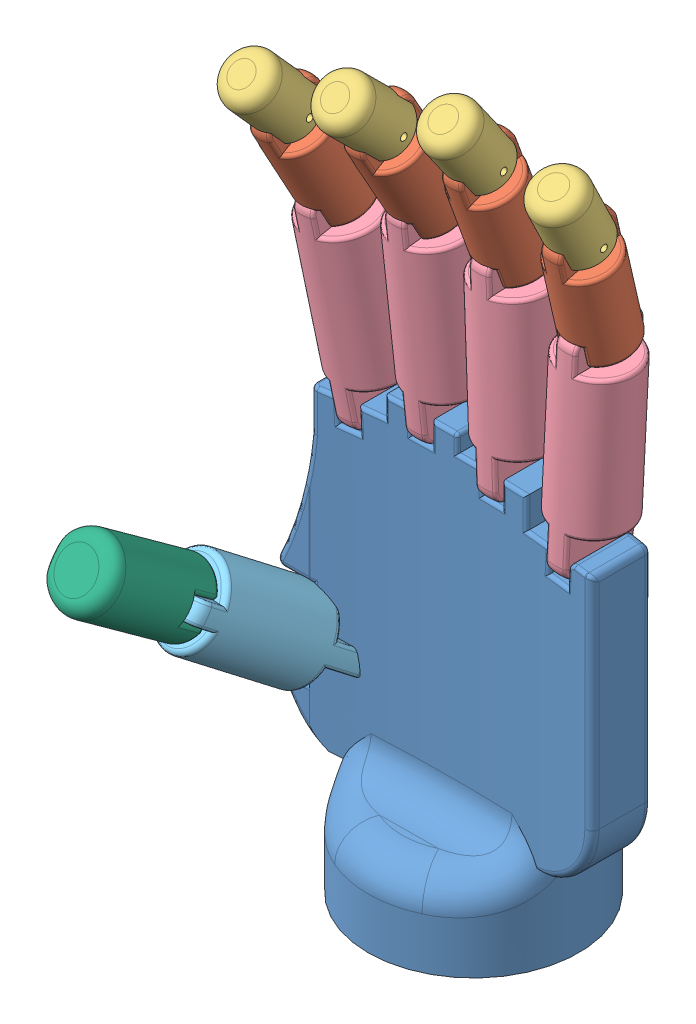
SolidWorks assembly Ensamblaje mano R, configuration Predeterminado. Lengths in mm.
Overall size (111.22 222.01 106.07).
15 component instances, 6 part files, 38 mates.
Components (placement in the parent):
- base de mano-1: base de mano [Predeterminado] at (3.3487 -3.4882 90) size (98.34 123.24 62)
- dedo 1.2-1: dedo 1.2 [Predeterminado] at (-6.9513 129.9804 122.3576) x (-1 0 0) z (0 -0.872955 -0.487801) size (18 18.07 36.32)
- dedo 1.1-1: dedo 1.1 [Predeterminado] at (-6.9513 140.0458 133.6656) x (-1 0 0) z (0 -0.704682 -0.709524) size (15 15 21)
- ded0 1.2-2: ded0 1.2 [Predeterminado] at (13.8487 99.4741 102.1423) x (1 0 0) z (0 -0.999383 -0.035119) size (21 21.03 64.5)
- dedo 1.2-2: dedo 1.2 [Predeterminado] at (13.8487 127.4833 113.3304) x (-1 0 0) z (0 -0.939617 -0.342227) size (18 18.07 36.32)
- dedo 1.1-2: dedo 1.1 [Predeterminado] at (13.8487 139.407 122.6313) x (1 0 0) z (0 -0.819026 -0.573756) size (15 15 21)
- ded0 1.2-3: ded0 1.2 [Predeterminado] at (37.5842 89.8924 100.0838) x (0.99863 -0.052336 0) z (-0.052336 -0.998629 -0.001373) size (21 21.03 64.5)
- dedo 1.2-3: dedo 1.2 [Predeterminado] at (39.0948 118.7167 108.6644) x (0.99863 -0.052336 0) z (-0.050534 -0.964246 -0.260145) size (18 18.07 36.32)
- dedo 1.1-3: dedo 1.1 [Predeterminado] at (39.782 131.8288 116.0778) x (0.99863 -0.052336 0) z (-0.046599 -0.889162 -0.455213) size (15 15 21)
- ded0 1.2-4: ded0 1.2 [Predeterminado] at (-30.7423 97.0382 110.1488) x (0.99863 0.052336 0) z (0.051607 -0.984711 -0.166374) size (21 21.03 64.5)
- dedo 1.2-4: dedo 1.2 [Predeterminado] at (-32.1183 123.2948 124.9268) x (-0.99863 -0.052336 0) z (0.04639 -0.885174 -0.462941) size (18 18.07 36.32)
- dedo 1.1-4: dedo 1.1 [Predeterminado] at (-32.6839 134.086 135.4832) x (0.99863 0.052336 0) z (0.039151 -0.747038 -0.663627) size (15 15 21)
- dedo 2.2-1: dedo 2.2 [Predeterminado] at (-34.4255 -31.0842 101.0623) x (0 0.819152 -0.573576) z (-0.241922 0.556539 0.79482) size (24 24.37 54.63)
- dedo 2.1-1: dedo 2.1 [Predeterminado] at (-48.9957 15.6091 167.7471) x (0 -0.819152 0.573576) z (0.069756 -0.572179 -0.817157) size (20 24.03 35.12)
- ded0 1.2-5: ded0 1.2 [Predeterminado] at (-6.9513 104.1554 106.5839) x (1 0 0) z (0 -0.994158 -0.107933) size (21 21.03 64.5)
Mates (geometry in assembly coordinates):
- Concéntrica3: concentric: cylinder of dedo 1.2-1 through (-3.9513 69.0706 182.5476) axis (-1 0 0) radius 1; cylinder of dedo 1.1-1 through (3.5487 69.0706 182.5476) axis (-1 0 0) radius 1
- Coincidente3: coincident: plane of dedo 1.2-1 through (-9.9513 59.8667 176.8653) normal (-1 0 0); plane of dedo 1.1-1 through (-9.9513 59.6122 183.2812) normal (1 0 0)
- Concéntrica4: concentric: cylinder of base de mano-1 through (23.3487 38.5118 100) axis (-1 0 0) radius 1; cylinder of ded0 1.2-2 through (7.8487 38.5118 100) axis (1 0 0) radius 1
- Coincidente4: coincident: plane of base de mano-1 through (10.8487 34.5118 110) normal (1 0 0); plane of ded0 1.2-2 through (10.8487 52.9112 101.9763) normal (-1 0 0)
- Concéntrica5: concentric: cylinder of ded0 1.2-2 through (10.8487 70.1008 148.6429) axis (1 0 0) radius 1; cylinder of dedo 1.2-2 through (19.8487 70.1008 148.6429) axis (-1 0 0) radius 1
- Coincidente5: coincident: plane of ded0 1.2-2 through (16.8487 76.0584 137.6198) normal (1 0 0); plane of dedo 1.2-2 through (16.8487 62.1839 153.87) normal (-1 0 0)
- Concéntrica6: concentric: cylinder of dedo 1.2-2 through (16.8487 77.8654 177.6207) axis (-1 0 0) radius 1; cylinder of dedo 1.1-2 through (3.3487 77.8654 177.6207) axis (1 0 0) radius 1
- Coincidente6: coincident: plane of dedo 1.2-2 through (16.8487 67.6191 174.1545) normal (1 0 0); plane of dedo 1.1-2 through (16.8487 86.8654 180.6207) normal (-1 0 0)
- Concéntrica7: concentric: cylinder of base de mano-1 through (24.9047 29.4733 100) axis (0.99863 -0.052336 0) radius 1; cylinder of ded0 1.2-3 through (28.3999 29.2901 100) axis (0.99863 -0.052336 0) radius 1
- Coincidente7: coincident: plane of base de mano-1 through (31.1865 25.1386 110) normal (0.99863 -0.052336 0); plane of ded0 1.2-3 through (32.1346 43.2301 103.4608) normal (-0.99863 0.052336 0)
- Concéntrica8: concentric: cylinder of ded0 1.2-3 through (32.7758 55.4645 151.66) axis (0.99863 -0.052336 0) radius 1; cylinder of dedo 1.2-3 through (29.7799 55.6215 151.66) axis (0.99863 -0.052336 0) radius 1
- Coincidente8: coincident: plane of ded0 1.2-3 through (39.1376 62.2107 141.3151) normal (0.99863 -0.052336 0); plane of dedo 1.2-3 through (39.261 64.5654 152.7166) normal (-0.99863 0.052336 0)
- Concéntrica9: concentric: cylinder of dedo 1.2-3 through (33.1033 61.7138 181) axis (0.99863 -0.052336 0) radius 1; cylinder of dedo 1.1-3 through (25.6136 62.1063 181) axis (0.99863 -0.052336 0) radius 1
- Coincidente9: coincident: plane of dedo 1.2-3 through (39.4902 68.9399 173.2546) normal (0.99863 -0.052336 0); plane of dedo 1.1-3 through (39.5662 70.3896 183.9937) normal (-0.99863 0.052336 0)
- Concéntrica10: concentric: cylinder of base de mano-1 through (-18.1073 37.468 100) axis (-0.99863 -0.052336 0) radius 1; cylinder of ded0 1.2-4 through (-33.5861 36.6568 100) axis (0.99863 0.052336 0) radius 1
- Coincidente10: coincident: plane of base de mano-1 through (-24.389 33.1333 110) normal (-0.99863 -0.052336 0); plane of ded0 1.2-4 through (-25.3047 50.6055 105.3948) normal (0.99863 0.052336 0)
- Concéntrica11: concentric: cylinder of ded0 1.2-4 through (-31.5798 55.6968 154.8311) axis (0.99863 0.052336 0) radius 1; cylinder of dedo 1.2-4 through (-22.5921 56.1678 154.8311) axis (-0.99863 -0.052336 0) radius 1
- Coincidente11: coincident: plane of ded0 1.2-4 through (-26.0299 64.4421 145.5728) normal (0.99863 0.052336 0); plane of dedo 1.2-4 through (-25.1199 47.0783 157.992) normal (-0.99863 -0.052336 0)
- Concéntrica12: concentric: cylinder of dedo 1.2-4 through (-25.6161 56.5478 184.8263) axis (-0.99863 -0.052336 0) radius 1; cylinder of dedo 1.1-4 through (-39.0976 55.8413 184.8263) axis (0.99863 0.052336 0) radius 1
- Coincidente12: coincident: plane of dedo 1.2-4 through (-31.1313 47.1402 178.9886) normal (-0.99863 -0.052336 0); plane of dedo 1.1-4 through (-32.0317 64.3195 189.7702) normal (0.99863 0.052336 0)
- Concéntrica13: concentric: cylinder of base de mano-1 through (-35.1513 -22.8613 98.8582) axis (0 -0.819152 0.573576) radius 1; cylinder of dedo 2.2-1 through (-35.1513 -26.1379 101.1525) axis (0 -0.819152 0.573576) radius 1
- Coincidente13: coincident: plane of base de mano-1 through (-32.1513 -28.4882 110) normal (0 0.819152 -0.573576); plane of dedo 2.2-1 through (-25.8863 -24.0445 116.3463) normal (0 -0.819152 0.573576)
- Concéntrica14: concentric: cylinder of dedo 2.2-1 through (-46.7635 0.5759 139.3038) axis (0 -0.819152 0.573576) radius 1; cylinder of dedo 2.1-1 through (-45.7958 -1.6502 136.1245) axis (0 -0.819152 0.573576) radius 1
- Coincidente14: coincident: plane of dedo 2.2-1 through (-33.7452 -5.6609 142.6008) normal (0 -0.819152 0.573576); plane of dedo 2.1-1 through (-30.0868 -3.8793 145.1452) normal (0 0.819152 -0.573576)
- Concéntrica15: concentric: cylinder of base de mano-1 through (2.5487 43.5118 100) axis (-1 0 0) radius 1; cylinder of ded0 1.2-5 through (-12.9513 43.5118 100) axis (1 0 0) radius 1
- Coincidente15: coincident: plane of base de mano-1 through (-3.9513 39.5118 110) normal (-1 0 0); plane of ded0 1.2-5 through (-3.9513 57.496 103.9611) normal (1 0 0)
- Concéntrica16: concentric: cylinder of dedo 1.2-1 through (-0.9513 68.0236 152.5659) axis (-1 0 0) radius 1; cylinder of ded0 1.2-5 through (-9.9513 68.0236 152.5659) axis (1 0 0) radius 1
- Coincidente16: coincident: plane of dedo 1.2-1 through (-9.9513 59.1338 155.8781) normal (1 0 0); plane of ded0 1.2-5 through (-9.9513 75.4573 142.4792) normal (-1 0 0)
- Ángulo2: planar angle = 0.401426 rad: cylinder of ded0 1.2-5 through (-6.9513 40.5293 99.6762) axis (0 0.994158 0.107933) radius 10.5; cylinder of dedo 1.2-1 through (-6.9513 98.5541 104.7967) axis (0 0.872955 0.487801) radius 9
- Ángulo3: planar angle = 0.279253 rad: cylinder of dedo 1.2-1 through (-6.9513 98.5541 104.7967) axis (0 0.872955 0.487801) radius 9; cylinder of dedo 1.1-1 through (-6.9513 125.2475 118.7656) axis (0 0.704682 0.709524) radius 7.5
- Ángulo5: planar angle = 0.314159 rad: cylinder of ded0 1.2-4 through (-27.4395 34.0167 99.5009) axis (-0.051607 0.984711 0.166374) radius 10.5; cylinder of dedo 1.2-4 through (-30.4483 91.4286 108.2609) axis (-0.04639 0.885174 0.462941) radius 9
- Ángulo6: planar angle = 0.244346 rad: cylinder of dedo 1.2-4 through (-30.4483 91.4286 108.2609) axis (-0.04639 0.885174 0.462941) radius 9; cylinder of dedo 1.1-4 through (-31.8617 118.3982 121.5471) axis (-0.039151 0.747038 0.663627) radius 7.5
- Ángulo7: planar angle = 2.897247 rad: line of base de mano-1 through (-38.1513 -36.4882 98.5748) axis (0 0.573576 0.819152); cylinder of dedo 2.2-1 through (-47.4893 -1.0311 143.9826) axis (0.241922 -0.556539 -0.79482) radius 12
- Ángulo8: planar angle = 2.96706 rad: cylinder of dedo 2.2-1 through (-47.4893 -1.0311 143.9826) axis (0.241922 -0.556539 -0.79482) radius 12; cylinder of dedo 2.1-1 through (-46.5543 -4.4172 139.1467) axis (-0.069756 0.572179 0.817157) radius 10
- Ángulo11: planar angle = 0.261799 rad: cylinder of ded0 1.2-3 through (34.2347 25.9802 99.9959) axis (0.052336 0.998629 0.001373) radius 10.5; cylinder of dedo 1.2-3 through (37.2756 84.0038 99.2992) axis (0.050534 0.964246 0.260145) radius 9
- Ángulo12: planar angle = 0.20944 rad: cylinder of dedo 1.2-3 through (37.2756 84.0038 99.2992) axis (0.050534 0.964246 0.260145) radius 9; cylinder of dedo 1.1-3 through (38.8034 113.1564 106.5183) axis (0.046599 0.889162 0.455213) radius 7.5
- Ángulo14: planar angle = 0.314159 rad: cylinder of ded0 1.2-2 through (13.8487 35.5136 99.8946) axis (0 0.999383 0.035119) radius 10.5; cylinder of dedo 1.2-2 through (13.8487 93.6571 101.0102) axis (0 0.939617 0.342227) radius 9
- Ángulo15: planar angle = 0.261799 rad: cylinder of dedo 1.2-2 through (13.8487 93.6571 101.0102) axis (0 0.939617 0.342227) radius 9; cylinder of dedo 1.1-2 through (13.8487 122.2074 110.5824) axis (0 0.819026 0.573756) radius 7.5
